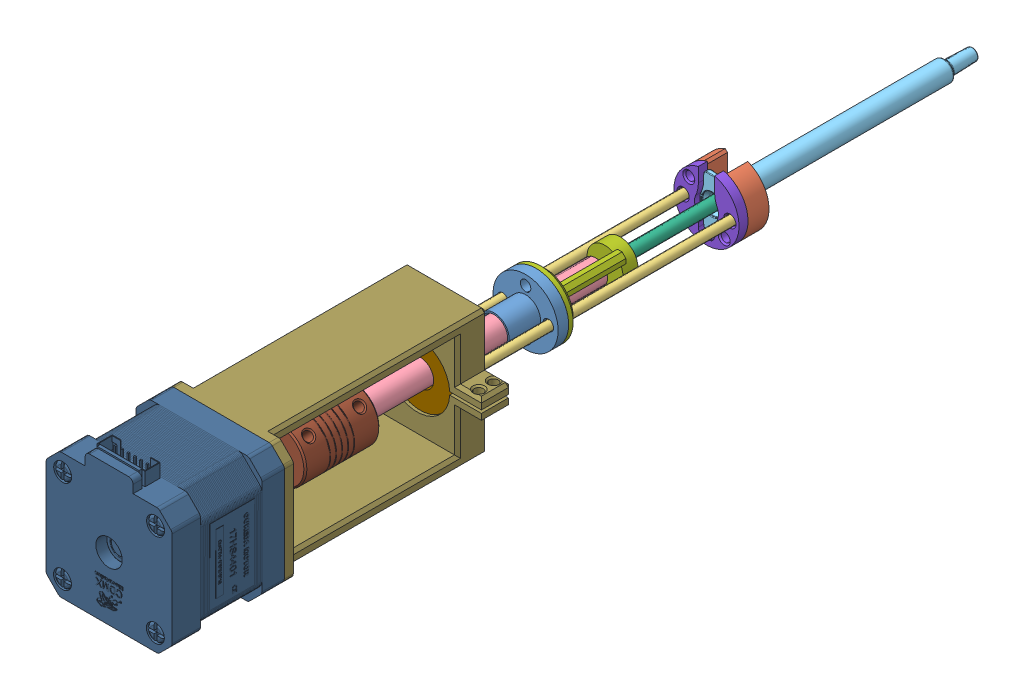
SolidWorks assembly Co_cau_nho_giot_1, configuration Default. Lengths in mm.
Overall size (42.9 46.77 288.22).
15 component instances, 14 part files, 34 mates.
Components (placement in the parent):
- Dai-oc-Vit-me-2: Dai-oc-Vit-me [Default] at (4.5651 -0.5781 49.6755) size (21.7 21.7 15)
- gia-2-truc-3mm-1: gia-2-truc-3mm [Default] at (4.5651 -0.5781 -16.1682) size (21.7 21.03 7)
- truc_3mm_10cm-4: truc_3mm_10cm [Default] at (12.3651 -0.5781 -13.6682) x (-0.346447 0.938069 0) z (0.938069 0.346447 0) size (3 100 3)
- truc_3mm_10cm-5: truc_3mm_10cm [Default] at (-3.2349 -0.5781 -13.6682) x (-0.346447 0.938069 0) z (0.938069 0.346447 0) size (3 100 3)
- truc-vit-me-8mm-1: truc-vit-me-8mm [Default] at (4.5651 -0.5781 130.6532) x (0.404094 0.914717 0) z (-0.914717 0.404094 0) size (8 100 8)
- xi_lanh_ong_chich-1: xi_lanh_ong_chich [Default] at (4.5651 -0.5781 -7.9682) x (0 -1 0) z (-1 0 0) size (17 87 10.2)
- bit_tong_ong_tiem-1: bit_tong_ong_tiem [Default] at (4.5651 -0.5781 14.0002) x (0.418589 0.908176 0) z (0.908176 -0.418589 0) size (10.2 89.28 10.2)
- mieng_day_ong_chich-1: mieng_day_ong_chich [Default] at (4.5651 -0.5781 50.6755) x (-1 0 0) z (0 0 -1) size (21.7 21.7 28)
- Part7^Co_cau_nho_giot_1-1: Part7^Co_cau_nho_giot_1 [Default] at (4.5651 -0.5781 -9.1682) (virtual)
- KEP_ONG_CHICH^Co_cau_nho_giot_1-1: KEP_ONG_CHICH^Co_cau_nho_giot_1 [Default] at (4.5651 -0.5781 -9.1682) size (21.7 21.35 3) (virtual)
- Part12^Co_cau_nho_giot_1-1: Part12^Co_cau_nho_giot_1 [Default] at origin (virtual)
- GIA_DO_TRU_3MM_DC-1: GIA_DO_TRU_3MM_DC [Default] at (4.5651 -0.5789 82.3318) x (1 -0.000104 0) z (0 0 1) size (21.7 21.7 7.01)
- Nema 17 Motor a Pasos 17HS4401-2: Nema 17 Motor a Pasos 17HS4401 [Default] at (4.5651 -0.5781 193.1532) x (0.999999 -0.001585 0) z (0 0 -1) size (42.2 46.7 62.65)
- 8mm_to 5mm_kaplin-1: 8mm_to 5mm_kaplin [Varsayılan] at (4.5651 -0.5781 129.6532) x (0.729719 -0.683747 0) z (-0.683747 -0.729719 0) size (18.93 25 18.11)
- Gia_Dong_co-1: Gia_Dong_co [Default] at (4.5651 -0.5781 155.6532) x (0.999999 -0.001585 0) z (0 0 -1) size (42.83 42 75.32)
Mates (geometry in assembly coordinates):
- Concentric21: concentric anti-aligned: cylinder of Dai-oc-Vit-me-2 through (4.5651 -0.5781 50.6755) axis (0 0 1) radius 10.85; cylinder of gia-2-truc-3mm-1 through (4.5651 -0.5781 -9.1682) axis (0 0 -1) radius 10.85
- Tangent9: tangent aligned: cylinder of Dai-oc-Vit-me-2 through (12.1651 -0.5781 38.6755) axis (0 0 1) radius 1.75; cylinder of gia-2-truc-3mm-1 through (12.3651 -0.5781 -9.1682) axis (0 0 -1) radius 1.55
- Coincident11: coincident anti-aligned: plane of gia-2-truc-3mm-1 through (12.3651 -0.5781 -13.6682) normal (0 0 1); plane of truc_3mm_10cm-4 through (12.3651 -0.5781 -13.6682) normal (0 0 -1)
- Concentric23: concentric aligned: cylinder of gia-2-truc-3mm-1 through (12.3651 -0.5781 -9.1682) axis (0 0 -1) radius 1.55; cylinder of truc_3mm_10cm-4 through (12.3651 -0.5781 86.3318) axis (0 0 -1) radius 1.5
- Coincident12: coincident anti-aligned: plane of gia-2-truc-3mm-1 through (-3.2349 -0.5781 -13.6682) normal (0 0 1); plane of truc_3mm_10cm-5 through (-3.2349 -0.5781 -13.6682) normal (0 0 -1)
- Concentric24: concentric aligned: cylinder of gia-2-truc-3mm-1 through (-3.2349 -0.5781 -9.1682) axis (0 0 -1) radius 1.55; cylinder of truc_3mm_10cm-5 through (-3.2349 -0.5781 86.3318) axis (0 0 -1) radius 1.5
- Concentric27: concentric anti-aligned: cylinder of Dai-oc-Vit-me-2 through (4.5651 -0.5781 64.6755) axis (0 0 -1) radius 4.5; cylinder of truc-vit-me-8mm-1 through (4.5651 -0.5781 30.6532) axis (0 0 1) radius 4
- Concentric29: concentric aligned: cylinder of truc-vit-me-8mm-1 through (4.5651 -0.5781 30.6532) axis (0 0 1) radius 4; cylinder of xi_lanh_ong_chich-1 through (4.5651 -0.5781 77.3277) axis (0 0 1) radius 3.35
- Coincident16: coincident anti-aligned: plane of gia-2-truc-3mm-1 through (4.5651 -0.5781 -9.1682) normal (0 0 1); plane of xi_lanh_ong_chich-1 through (5.0428 14.6097 -9.1682) normal (0 0 -1)
- Concentric30: concentric anti-aligned: cylinder of xi_lanh_ong_chich-1 through (4.5651 -0.5781 77.3277) axis (0 0 1) radius 3.35; cylinder of bit_tong_ong_tiem-1 through (4.5651 -0.5781 -61.4245) axis (0 0 -1) radius 1.95
- InPlace3: in place: plane of ? through (4.5651 -0.5781 42.5794) normal (0 0 -1); plane of ? through (0 0 42.5794) normal (0 0 -1); moOrthogonalPlaneRef_w of ? through (4.5651 -0.5781 42.5794) normal (0 0 -1); plane of ? through (0 0 42.5794) normal (0 1 0); plane of ? through (4.5651 -0.5781 42.5794) normal (0 0 -1); plane of ? through (0 0 42.5794) normal (-1 0 0); plane of Dai-oc-Vit-me-2 through (4.5651 -0.5781 50.6755) normal (0 0 -1); unknown of mieng_day_ong_chich-1
- Coincident18: coincident aligned: plane of Dai-oc-Vit-me-2; plane of mieng_day_ong_chich-1
- Coincident19: coincident aligned: moOrthogonalPlaneRef_w of Dai-oc-Vit-me-2 through (4.5651 -0.5781 50.6755) normal (0 1 0); plane of mieng_day_ong_chich-1 through (4.5651 -0.5781 50.6755) normal (0 1 0)
- Coincident20: coincident anti-aligned: moOrthogonalPlaneRef_w of Dai-oc-Vit-me-2 through (4.5651 -0.5781 50.6755) normal (1 0 0); plane of mieng_day_ong_chich-1 through (4.5651 -0.5781 50.6755) normal (-1 0 0)
- Concentric31: concentric aligned: cylinder of Dai-oc-Vit-me-2 through (4.5651 -0.5781 50.6755) axis (0 0 1) radius 10.85; cylinder of mieng_day_ong_chich-1 through (4.5651 -0.5781 47.6755) axis (0 0 1) radius 10.85
- InPlace4: in place: plane of gia-2-truc-3mm-1 through (4.5651 -0.5781 -9.1682) normal (0 0 1); plane of ? through (0 0 -9.1682) normal (0 0 1); plane of gia-2-truc-3mm-1 through (4.5651 -0.5781 -9.1682) normal (0 0 1); plane of ? through (0 0 -9.1682) normal (0 1 0); plane of gia-2-truc-3mm-1 through (4.5651 -0.5781 -9.1682) normal (0 0 1); plane of ? through (0 0 -9.1682) normal (1 0 0); plane of gia-2-truc-3mm-1 through (4.5651 -0.5781 -9.1682) normal (0 0 1); unknown of ?
- Coincident24: coincident aligned: plane of gia-2-truc-3mm-1; plane of Part7^Co_cau_nho_giot_1-1
- Coincident25: coincident aligned: moOrthogonalPlaneRef_w of gia-2-truc-3mm-1 through (4.5651 -0.5781 -9.1682) normal (0 1 0); plane of Part7^Co_cau_nho_giot_1-1 through (4.5651 -0.5781 -9.1682) normal (0 1 0)
- Coincident26: coincident anti-aligned: moOrthogonalPlaneRef_w of gia-2-truc-3mm-1 through (4.5651 -0.5781 -9.1682) normal (-1 0 0); plane of Part7^Co_cau_nho_giot_1-1 through (4.5651 -0.5781 -9.1682) normal (1 0 0)
- InPlace5: in place: plane of gia-2-truc-3mm-1 through (4.5651 -0.5781 -9.1682) normal (0 0 1); plane of ? through (0 0 -9.1682) normal (0 0 1); plane of gia-2-truc-3mm-1 through (4.5651 -0.5781 -9.1682) normal (0 0 1); plane of ? through (0 0 -9.1682) normal (0 1 0); plane of gia-2-truc-3mm-1 through (4.5651 -0.5781 -9.1682) normal (0 0 1); plane of ? through (0 0 -9.1682) normal (1 0 0); plane of gia-2-truc-3mm-1 through (4.5651 -0.5781 -9.1682) normal (0 0 1); unknown of ?
- Coincident27: coincident aligned: plane of gia-2-truc-3mm-1; plane of KEP_ONG_CHICH^Co_cau_nho_giot_1-1
- Coincident28: coincident aligned: moOrthogonalPlaneRef_w of gia-2-truc-3mm-1 through (4.5651 -0.5781 -9.1682) normal (0 1 0); plane of KEP_ONG_CHICH^Co_cau_nho_giot_1-1 through (4.5651 -0.5781 -9.1682) normal (0 1 0)
- Coincident29: coincident anti-aligned: moOrthogonalPlaneRef_w of gia-2-truc-3mm-1 through (4.5651 -0.5781 -9.1682) normal (-1 0 0); plane of KEP_ONG_CHICH^Co_cau_nho_giot_1-1 through (4.5651 -0.5781 -9.1682) normal (1 0 0)
- Coincident44: coincident anti-aligned: plane of truc_3mm_10cm-5 through (-3.2349 -0.5781 86.3318) normal (0 0 1); plane of GIA_DO_TRU_3MM_DC-1 through (-3.2349 -0.5781 86.3318) normal (0 0 -1)
- Concentric36: concentric aligned: cylinder of truc_3mm_10cm-5 through (-3.2349 -0.5781 86.3318) axis (0 0 -1) radius 1.5; cylinder of GIA_DO_TRU_3MM_DC-1 through (-3.2349 -0.5781 89.3318) axis (0 0 -1) radius 1.55
- Coincident45: coincident anti-aligned: plane of bit_tong_ong_tiem-1 through (5.6325 1.7377 26.1755) normal (0 0 1); plane of mieng_day_ong_chich-1 through (4.5651 -0.5781 26.1755) normal (0 0 -1)
- Concentric38: concentric anti-aligned: cylinder of truc-vit-me-8mm-1 through (4.5651 -0.5781 30.6532) axis (0 0 1) radius 4; cylinder of Nema 17 Motor a Pasos 17HS4401-2 through (4.5651 -0.5781 155.6532) axis (0 0 -1) radius 2.5
- Concentric39: concentric anti-aligned: cylinder of Nema 17 Motor a Pasos 17HS4401-2 through (4.5651 -0.5781 155.6532) axis (0 0 -1) radius 2.5; cylinder of 8mm_to 5mm_kaplin-1 through (4.5651 -0.5781 130.6532) axis (0 0 1) radius 2.5
- Coincident46: coincident aligned: plane of Nema 17 Motor a Pasos 17HS4401-2 through (4.5651 -0.5781 130.6532) normal (0 0 -1); plane of 8mm_to 5mm_kaplin-1 through (4.5651 -0.5781 130.6532) normal (0 0 -1)
- Coincident47: coincident anti-aligned: plane of truc-vit-me-8mm-1 through (4.5651 -0.5781 130.6532) normal (0 0 1); plane of 8mm_to 5mm_kaplin-1 through (4.5651 -0.5781 130.6532) normal (0 0 -1)
- InPlace11: in place: plane of ? through (4.5651 -0.5781 155.6532) normal (0 0 -1); plane of ? through (0 0 155.6532) normal (0 0 -1); plane of ? through (4.5651 -0.5781 155.6532) normal (0 0 -1); plane of ? through (0 0 155.6532) normal (0 1 0); plane of ? through (4.5651 -0.5781 155.6532) normal (0 0 -1); plane of ? through (0 0 155.6532) normal (-1 0 0); plane of Nema 17 Motor a Pasos 17HS4401-2 through (4.5651 -0.5781 155.6532) normal (0 0 -1); unknown of Gia_Dong_co-1
- Coincident51: coincident aligned: plane of Nema 17 Motor a Pasos 17HS4401-2; plane of Gia_Dong_co-1
- Coincident52: coincident aligned: moOrthogonalPlaneRef_w of Nema 17 Motor a Pasos 17HS4401-2; plane of Part70^Co_cau_nho_giot_1-1 through (4.5651 -0.5781 155.6532) normal (-0.001585 -0.999999 0)
- Coincident53: coincident anti-aligned: moOrthogonalPlaneRef_w of Nema 17 Motor a Pasos 17HS4401-2; plane of Part70^Co_cau_nho_giot_1-1 through (4.5651 -0.5781 155.6532) normal (0.999999 -0.001585 0)
